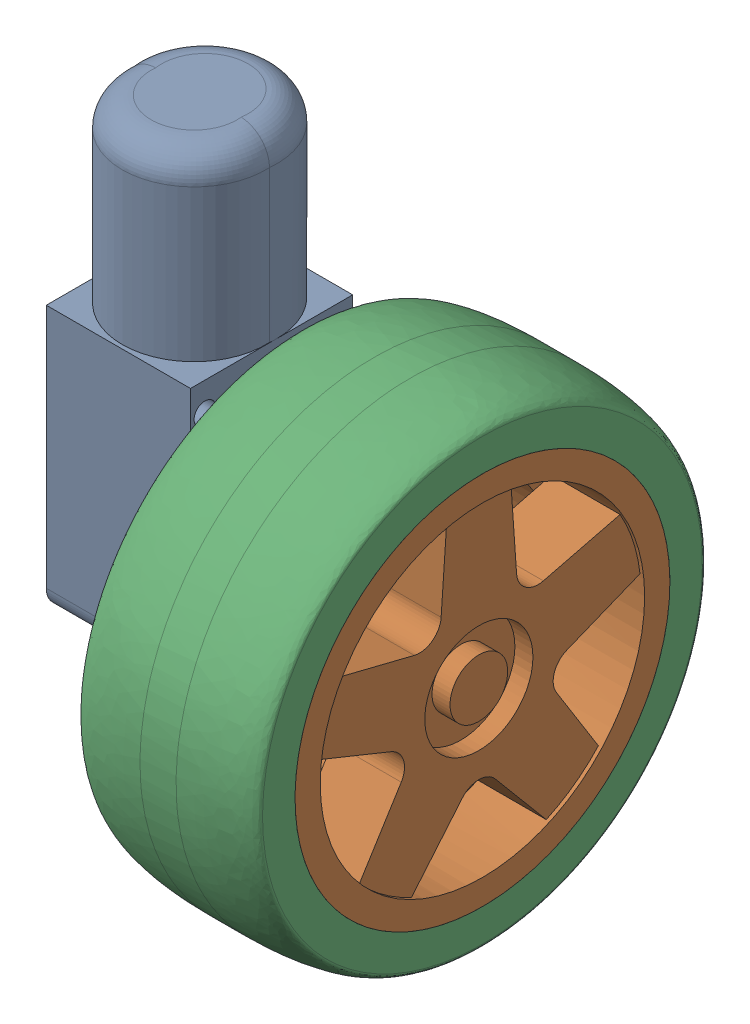
SolidWorks assembly Assem6, configuration Default. Lengths in mm.
Overall size (58.65 88.69 72.93).
3 component instances, 3 part files, 3 mates.
Components (placement in the parent):
- Motor Servo-1: Motor Servo [Default] at (64 22.7641 -141.5) x (0 1 0) z (-1 0 0) size (67.23 22.5 38.2)
- Wheel-1: Wheel [Default] at (88.5 -25.2037 -191.1221) x (0 0 -1) z (1 0 0) size (52 52 30)
- Tire-1: Tire [Default] at (88.5 -18.5822 -64.8858) x (0 0.104619 0.994512) z (-1 0 0) size (66.35 66.35 25.1)
Mates (geometry in assembly coordinates):
- Concentric54: concentric: cylinder of assembly; circle of Motor Servo-1; cylinder of Wheel-1 through (83.5 -31.5 -127.5) axis (1 0 0) radius 5
- Concentric55: concentric: cylinder of Wheel-1 through (-4.8381 -31.5 -127.5) axis (1 0 0) radius 26; cylinder of Tire-1 through (205.4239 -31.5 -127.5) axis (-1 0 0) radius 26
- Coincident396: coincident: plane of Wheel-1 through (88.5 -31.5 -127.5) normal (-1 0 0); plane of Tire-1 through (88.5 -31.5 -127.5) normal (-1 0 0)
